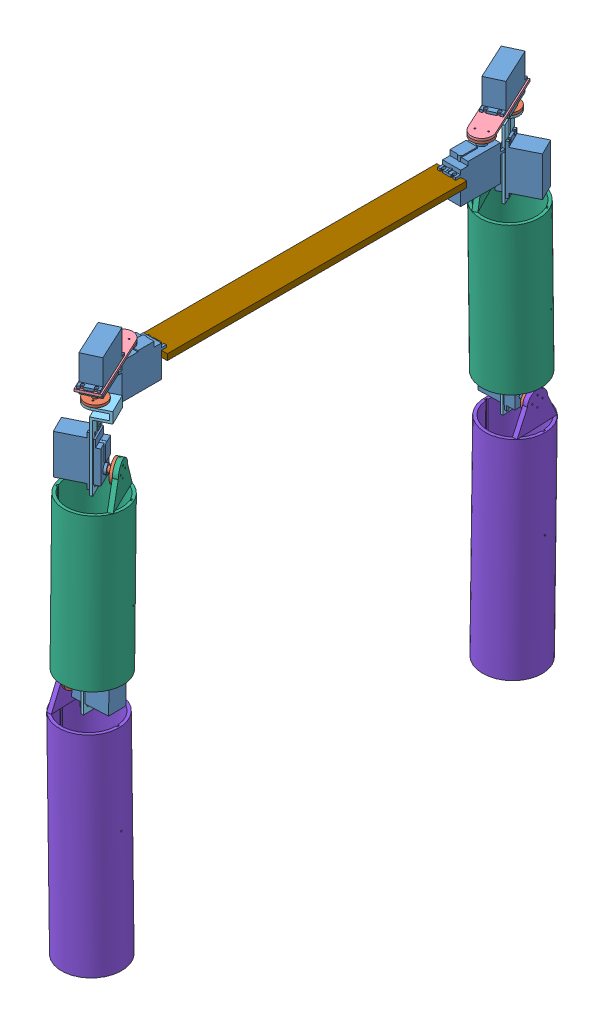
SolidWorks assembly THE MAIN, configuration Default. Lengths in mm.
Overall size (215.79 872.9 916.17).
49 component instances, 9 part files, 6 mates.
Components (placement in the parent):
- Main-1: Main [Default] at (-444.4937 294.6444 34.3762) size (137.57 872.9 216.43)
  - EHT Servo-1: EHT Servo [Default] at (-20.6461 -47.7325 42.6943) size (30.2 70.3 82.7)
  - Servo Fitting1-1: Servo Fitting1 [Default] at (-5.5461 22.5675 -7.5557) x (0.906958 0 -0.421221) z (0.421221 0 0.906958) size (35 10.9 35)
  - slotted countersunk flat head screw_iso-1: slotted countersunk flat head screw_iso [M3x10] at (-5.5461 24.6175 -7.5557) x (0 -1 0) z (-0.907999 0 0.418972) size (10 5.5 5.44)
  - Fixture1-1: Fixture1 [Default] at (-5.5461 26.5675 -7.5557) x (0.906958 0 -0.421221) z (0.421221 0 0.906958) size (35 4 135.5)
  - EHT Servo Assembly-2: EHT Servo Assembly [Default] at (-31.6294 28.2259 -82.9932) x (-0.906958 0 0.421221) z (0.421221 0 0.906958) size (35.9 74.3 82.7)
    - EHT Servo-1: EHT Servo [Default] at (-6.9806 -48.3416 37.5554) size (30.2 70.3 82.7)
    - Servo Fitting1-1: Servo Fitting1 [Default] at (8.1194 21.9584 -12.6946) x (-0.026119 0 0.999659) z (-0.999659 0 -0.026119) size (35 10.9 35)
    - slotted countersunk flat head screw_iso-1: slotted countersunk flat head screw_iso [M3x10] at (8.1194 24.0084 -12.6946) x (0 -1 0) z (0.028596 0 -0.999591) size (10 5.5 5.44)
  - Fixture2-2: Fixture2 [Default] at (-44.3406 2.2675 -91.0866) x (0.444766 0 0.895647) z (0.895647 0 -0.444766) size (35 128 45)
  - EHT Servo Assembly-4: EHT Servo Assembly [Default] at (-41.4831 -82.1378 -83.4402) x (-0.444766 0 -0.895647) z (0 1 0) size (35.9 74.3 82.7)
    - EHT Servo-1: EHT Servo [Default] at (-6.9806 -48.3416 37.5554) size (30.2 70.3 82.7)
    - Servo Fitting1-1: Servo Fitting1 [Default] at (8.1194 21.9584 -12.6946) x (-0.026119 0 0.999659) z (-0.999659 0 -0.026119) size (35 10.9 35)
    - slotted countersunk flat head screw_iso-1: slotted countersunk flat head screw_iso [M3x10] at (8.1194 24.0084 -12.6946) x (0 -1 0) z (0.028596 0 -0.999591) size (10 5.5 5.44)
  - New Arm-1: New Arm [Default] at (-46.4265 -382.2344 -98.4349) x (-0.895647 0 0.444766) z (0.011617 0.999659 0.023394) size (100 100 305)
  - Motor Assembly-2: Motor Assembly [Default] at (-41.7886 -288.5986 -74.2303) x (-0.895647 0 0.444766) z (0.011617 0.999659 0.023394) size (94.48 90 173.9)
    - Motor-1: Motor [Default] at (-6.6114 -21.2878 17.9514) size (94.48 90 41.9)
    - Servo Fitting1-1: Servo Fitting1 [Default] at (-6.6114 -21.2878 -18.9486) x (-0.40842 -0.912794 0) z (0.912794 -0.40842 0) size (35 10.9 35)
    - Fixture2-1: Fixture2 [Default] at (-6.6114 -21.2878 -22.9486) x (0.40842 0.912794 0) z (-0.912794 0.40842 0) size (35 128 45)
  - EHT Servo Assembly3-2: EHT Servo Assembly3 [Default] at (-39.1972 -393.6902 -108.2701) x (0.040041 -0.023842 0.998914) z (0.011617 0.999659 0.023394) size (35.9 74.3 82.7)
    - EHT Servo-1: EHT Servo [Default] at (-5.8382 -48.3416 35.9233) size (30.2 70.3 82.7)
    - Servo Fitting1-1: Servo Fitting1 [Default] at (9.2618 21.9584 -14.3267) x (-0.026119 0 0.999659) z (-0.999659 0 -0.026119) size (35 10.9 35)
    - slotted countersunk flat head screw_iso-1: slotted countersunk flat head screw_iso [M3x10] at (9.2618 24.0084 -14.3267) x (0 -1 0) z (0.028596 0 -0.999591) size (10 5.5 5.44)
  - Forearm-1: Forearm [Default] at (-44.2705 -695.6918 -98.4853) x (0.999131 -0.010668 -0.040304) z (0.010567 0.999941 -0.002705) size (100 100 405)
- Back-1: Back [Default] at (-425.0399 279.0119 77.0205) x (0 0 1) z (-1 0 0) size (500 10 50)
- Main-2: Main [Default] at (-455.586 294.6444 619.6648) x (-1 0 0) z (0 0 -1) size (137.57 872.9 216.43)
  - EHT Servo-1: EHT Servo [Default] at (-20.6461 -47.7325 42.6943) size (30.2 70.3 82.7)
  - Servo Fitting1-1: Servo Fitting1 [Default] at (-5.5461 22.5675 -7.5557) x (0.906958 0 -0.421221) z (0.421221 0 0.906958) size (35 10.9 35)
  - slotted countersunk flat head screw_iso-1: slotted countersunk flat head screw_iso [M3x10] at (-5.5461 24.6175 -7.5557) x (0 -1 0) z (-0.907999 0 0.418972) size (10 5.5 5.44)
  - Fixture1-1: Fixture1 [Default] at (-5.5461 26.5675 -7.5557) x (0.906958 0 -0.421221) z (0.421221 0 0.906958) size (35 4 135.5)
  - EHT Servo Assembly-2: EHT Servo Assembly [Default] at (-31.6294 28.2259 -82.9932) x (-0.906958 0 0.421221) z (0.421221 0 0.906958) size (35.9 74.3 82.7)
    - EHT Servo-1: EHT Servo [Default] at (-6.9806 -48.3416 37.5554) size (30.2 70.3 82.7)
    - Servo Fitting1-1: Servo Fitting1 [Default] at (8.1194 21.9584 -12.6946) x (-0.026119 0 0.999659) z (-0.999659 0 -0.026119) size (35 10.9 35)
    - slotted countersunk flat head screw_iso-1: slotted countersunk flat head screw_iso [M3x10] at (8.1194 24.0084 -12.6946) x (0 -1 0) z (0.028596 0 -0.999591) size (10 5.5 5.44)
  - Fixture2-2: Fixture2 [Default] at (-44.3406 2.2675 -91.0866) x (0.444766 0 0.895647) z (0.895647 0 -0.444766) size (35 128 45)
  - EHT Servo Assembly-4: EHT Servo Assembly [Default] at (-41.4831 -82.1378 -83.4402) x (-0.444766 0 -0.895647) z (0 1 0) size (35.9 74.3 82.7)
    - EHT Servo-1: EHT Servo [Default] at (-6.9806 -48.3416 37.5554) size (30.2 70.3 82.7)
    - Servo Fitting1-1: Servo Fitting1 [Default] at (8.1194 21.9584 -12.6946) x (-0.026119 0 0.999659) z (-0.999659 0 -0.026119) size (35 10.9 35)
    - slotted countersunk flat head screw_iso-1: slotted countersunk flat head screw_iso [M3x10] at (8.1194 24.0084 -12.6946) x (0 -1 0) z (0.028596 0 -0.999591) size (10 5.5 5.44)
  - New Arm-1: New Arm [Default] at (-46.4265 -382.2344 -98.4349) x (-0.895647 0 0.444766) z (0.011617 0.999659 0.023394) size (100 100 305)
  - Motor Assembly-2: Motor Assembly [Default] at (-41.7886 -288.5986 -74.2303) x (-0.895647 0 0.444766) z (0.011617 0.999659 0.023394) size (94.48 90 173.9)
    - Motor-1: Motor [Default] at (-6.6114 -21.2878 17.9514) size (94.48 90 41.9)
    - Servo Fitting1-1: Servo Fitting1 [Default] at (-6.6114 -21.2878 -18.9486) x (-0.40842 -0.912794 0) z (0.912794 -0.40842 0) size (35 10.9 35)
    - Fixture2-1: Fixture2 [Default] at (-6.6114 -21.2878 -22.9486) x (0.40842 0.912794 0) z (-0.912794 0.40842 0) size (35 128 45)
  - EHT Servo Assembly3-2: EHT Servo Assembly3 [Default] at (-39.1972 -393.6902 -108.2701) x (0.040041 -0.023842 0.998914) z (0.011617 0.999659 0.023394) size (35.9 74.3 82.7)
    - EHT Servo-1: EHT Servo [Default] at (-5.8382 -48.3416 35.9233) size (30.2 70.3 82.7)
    - Servo Fitting1-1: Servo Fitting1 [Default] at (9.2618 21.9584 -14.3267) x (-0.026119 0 0.999659) z (-0.999659 0 -0.026119) size (35 10.9 35)
    - slotted countersunk flat head screw_iso-1: slotted countersunk flat head screw_iso [M3x10] at (9.2618 24.0084 -14.3267) x (0 -1 0) z (0.028596 0 -0.999591) size (10 5.5 5.44)
  - Forearm-1: Forearm [Default] at (-44.2705 -695.6918 -98.4853) x (0.999131 -0.010668 -0.040304) z (0.010567 0.999941 -0.002705) size (100 100 405)
Mates (geometry in assembly coordinates):
- Concentric1: concentric aligned: cylinder of Main-1/EHT Servo-1 through (-458.9399 286.0119 81.2205) axis (0 1 0) radius 2.75; cylinder of Back-1 through (-458.9399 279.0119 81.2205) axis (0 1 0) radius 2.5
- Concentric2: concentric aligned: cylinder of Main-1/EHT Servo-1 through (-441.1399 286.0119 81.2205) axis (0 1 0) radius 2.75; cylinder of Back-1 through (-441.1399 279.0119 81.2205) axis (0 1 0) radius 2.5
- Coincident1: coincident anti-aligned: plane of Main-1/EHT Servo-1 through (-434.9399 289.0119 85.3705) normal (0 -1 0); plane of Back-1 through (-425.0399 289.0119 77.0205) normal (0 1 0)
- Concentric3: concentric aligned: cylinder of Back-1 through (-441.1399 279.0119 572.8205) axis (0 1 0) radius 2.5; cylinder of Main-2/EHT Servo-1 through (-441.1399 286.0119 572.8205) axis (0 1 0) radius 2.75
- Concentric4: concentric aligned: cylinder of Back-1 through (-458.9399 279.0119 572.8205) axis (0 1 0) radius 2.5; cylinder of Main-2/EHT Servo-1 through (-458.9399 286.0119 572.8205) axis (0 1 0) radius 2.75
- Coincident3: coincident anti-aligned: plane of Back-1 through (-425.0399 289.0119 77.0205) normal (0 1 0); plane of Main-2/EHT Servo-1 through (-465.1399 289.0119 568.6705) normal (0 -1 0)
